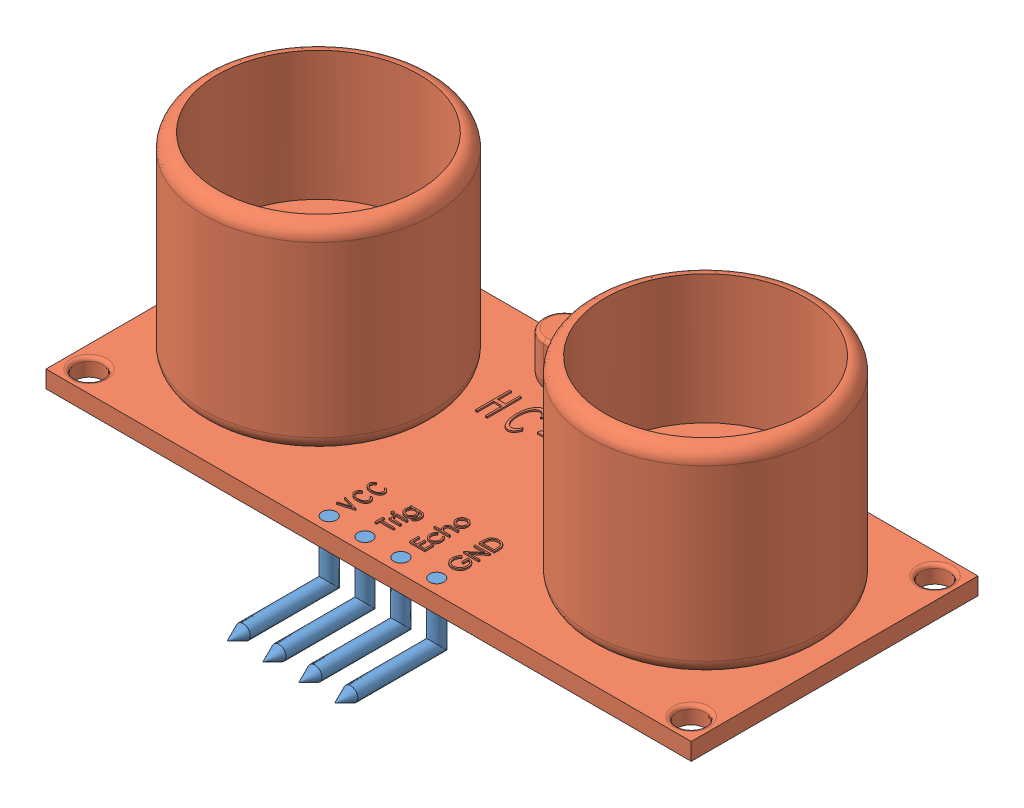
SolidWorks assembly Assem3_1, configuration Default. Lengths in mm.
Overall size (45 18.3 26.12).
7 component instances, 3 part files, 0 mates.
Components (placement in the parent):
- pin header-1: pin header [Default] at (-4.1109 -10.7267 50.9724) x (0 0 -1) z (1 0 0) size (7.62 4.5 1)
- UltraSonic-1: UltraSonic [Default] at (-2.8609 -7.9267 1.7996) size (45 15 20)
- pin header-2: pin header [Default] at (0.8891 -10.7267 50.9724) x (0 0 -1) z (1 0 0) size (7.62 4.5 1)
- part2_1-1: part2_1 [Default] at (-16.3609 -2.9267 1.7996) x (0.862539 0 -0.505991) z (0.505991 0 0.862539) size (8 0.65 8)
- pin header-3: pin header [Default] at (-6.6109 -10.7267 50.9724) x (0 0 -1) z (1 0 0) size (7.62 4.5 1)
- pin header-4: pin header [Default] at (-1.6109 -10.7267 50.9724) x (0 0 -1) z (1 0 0) size (7.62 4.5 1)
- part2_1-2: part2_1 [Default] at (10.6391 -2.6926 1.7996) x (0.988186 0 -0.153259) z (0.153259 0 0.988186) size (8 0.65 8)
